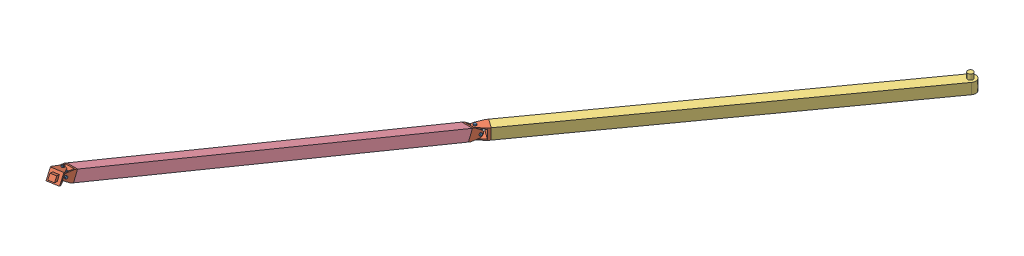
SolidWorks assembly leg_assy, configuration Default. Lengths in mm.
Overall size (412.05 352.92 1358.52).
10 component instances, 4 part files, 9 mates.
Components (placement in the parent):
- U_assy-1: U_assy [Default] at origin size (37.38 32.4 61.75) (flexible)
  - connector_new-2: connector_new [Default] at (661.9873 -10 0) size (23.51 23.51 14.4)
  - U_leg-3: U_leg [Default] at (661.9873 -2.4046 18.5016) x (0 -0.92508 0.379772) z (1 0 0) size (20 35.93 20)
  - U_leg-4: U_leg [Default] at (673.6593 -10 -16.2408) x (-0.81204 0 -0.583602) z (0 1 0) size (20 35.93 20)
- active_link-2: active_link [Default] at (1048.3241 0 -537.5602) x (-0.583602 0 0.81204) z (-0.81204 0 -0.583602) size (651.99 30 20)
- passive_link-2: passive_link [Default] at (661.9873 -2.4046 18.5016) x (0 0.379772 0.92508) z (0 0.92508 -0.379772) size (796 20 20)
- U_assy-3: U_assy [Default] at (0 657.6054 -126.8888) x (1 0 0) z (0 -0.409849 -0.912153) size (31.79 23.51 61.91) (flexible)
  - connector_new-2: connector_new [Default] at (661.9873 688.3292 -677.6764) size (23.51 23.51 14.4)
  - U_leg-3: U_leg [Default] at (661.9873 687.6745 -657.6871) x (0 -0.999464 -0.032734) z (1 0 0) size (20 35.93 20)
  - U_leg-4: U_leg [Default] at (669.1142 688.3292 -696.3634) x (-0.934354 0 -0.356346) z (0 1 0) size (20 35.93 20)
Mates (geometry in assembly coordinates):
- Coincident1: coincident anti-aligned: plane of U_assy-1/U_leg-4 through (673.6593 -10 -16.2408) normal (0.583602 0 -0.81204); plane of active_link-2 through (673.6593 -20 -16.2408) normal (-0.583602 0 0.81204)
- Coincident2: coincident anti-aligned: plane of U_assy-1/U_leg-4 through (683.5555 -15 -21.4432) normal (0 -1 0); plane of active_link-2 through (675.4351 -15 -27.2792) normal (0 1 0)
- Coincident3: coincident anti-aligned: plane of U_assy-1/U_leg-4 through (683.5555 -5 -21.4432) normal (0.81204 0 0.583602); plane of active_link-2 through (683.5555 -15 -21.4432) normal (-0.81204 0 -0.583602)
- Coincident4: coincident anti-aligned: plane of U_assy-1/U_leg-3 through (661.9873 -2.4046 18.5016) normal (0 0.379772 0.92508); plane of passive_link-2 through (661.9873 -2.4046 18.5016) normal (0 -0.379772 -0.92508)
- Coincident5: coincident anti-aligned: plane of U_assy-1/U_leg-3 through (656.9873 6.0185 25.8536) normal (-1 0 0); plane of passive_link-2 through (656.9873 -3.2323 29.6513) normal (1 0 0)
- Coincident6: coincident anti-aligned: plane of U_assy-1/U_leg-3 through (656.9873 -3.2323 29.6513) normal (0 -0.92508 0.379772); plane of passive_link-2 through (666.9873 -3.2323 29.6513) normal (0 0.92508 -0.379772)
- Coincident7: coincident anti-aligned: plane of passive_link-2 through (661.9873 299.8936 754.8655) normal (0 0.379772 0.92508); plane of U_assy-3/U_leg-3 through (661.9873 299.8936 754.8655) normal (0 -0.379772 -0.92508)
- Coincident8: coincident anti-aligned: plane of passive_link-2 through (666.9873 300.7212 743.7159) normal (0 -0.92508 0.379772); plane of U_assy-3/U_leg-3 through (656.9873 300.7212 743.7159) normal (0 0.92508 -0.379772)
- Coincident9: coincident anti-aligned: plane of passive_link-2 through (656.9873 300.7212 743.7159) normal (1 0 0); plane of U_assy-3/U_leg-3 through (656.9873 291.4704 747.5136) normal (-1 0 0)
